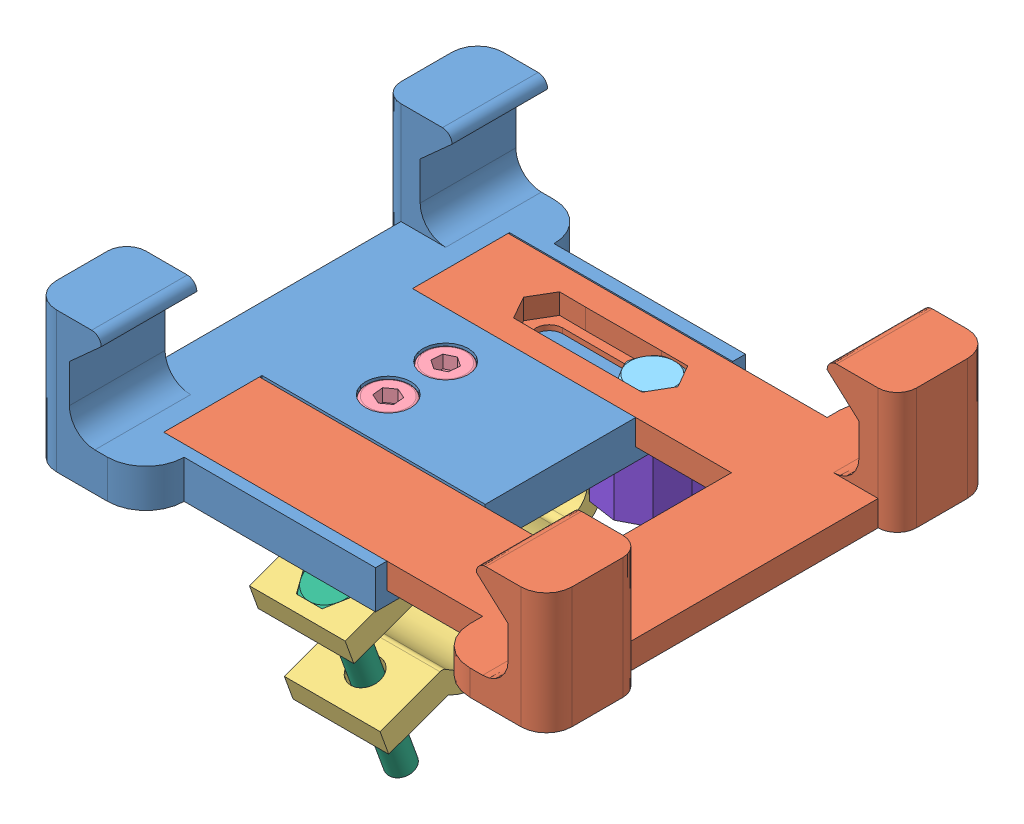
SolidWorks assembly Assemblagefinal, configuration Défaut. Lengths in mm.
Overall size (81 69.3 70.2).
12 component instances, 8 part files, 29 mates.
Components (placement in the parent):
- Support_droitV3_Upg-1: Support_droitV3_Upg [Défaut] at (-15.4658 -25.111 70) size (48 22 70)
- Support_gaucheV3_Upg-1: Support_gaucheV3_Upg [Défaut] at (10.8823 -7.9295 140.2) x (-1 0 0) z (0 0 -1) size (68 19 70)
- charnière_bisbis-1: charnière_bisbis [Défaut] at (-2.1366 -28.9295 101.2148) x (0.000205 -0.34202 0.939693) z (-1 0 0.000218) size (39.54 36.9 15)
- Vis à tête cylindrique à six pans creux Chc M4 - 10-1: Vis à tête cylindrique à six pans creux Chc M4 - 10 [Défaut] at (-9.6348 -8.1295 109.5) x (0.409825 0 -0.912164) z (0 -1 0) size (7 7 14)
- Vis à tête cylindrique à six pans creux Chc M4 - 10-2: Vis à tête cylindrique à six pans creux Chc M4 - 10 [Défaut] at (-9.6348 -8.1295 100.5) x (0.996961 0 0.077905) z (0 -1 0) size (7 7 14)
- Vis à tête hexagonale H M4 - 10-1: Vis à tête hexagonale H M4 - 10 [Défaut] at (7.8652 -7.1295 85.6045) x (0 0 -1) z (0 -1 0) size (7 8.08 12.8)
- Vis à tête hexagonale H M4 - 30-1: Vis à tête hexagonale H M4 - 30 [Défaut] at (-9.633 -27.2448 117.6392) x (-0.865923 -0.17101 0.470035) z (-0.000075 -0.939693 -0.34202) size (7 8.08 32.8)
- Ecrou M4-1: Ecrou M4 [Défaut] at (-9.6343 -43.4075 111.7564) x (0.866128 -0.17101 0.469658) z (0.000075 0.939693 0.34202) size (7 8.08 3.2)
- Ecrou M4-2: Ecrou M4 [Défaut] at (-9.6348 -16.1295 100.5) x (0.865916 0 -0.500189) z (0 -1 0) size (7 8.08 3.2)
- Ecrou M4-3: Ecrou M4 [Défaut] at (-9.6348 -16.1295 109.5) x (0.854192 0 -0.519958) z (0 -1 0) size (7 8.08 3.2)
- vissage-1: vissage [Défaut] at (7.8652 -19.9295 85.6045) x (1 0 0) z (0 1 0) size (14.56 14.51 10)
- Ecrou M4-4: Ecrou M4 [Défaut] at (7.8652 -17.1295 85.6045) x (0.929743 0 -0.368209) z (0 -1 0) size (7 8.08 3.2)
Mates (geometry in assembly coordinates):
- Coïncidente4: coincident anti-aligned: plane of Support_droitV3_Upg-1 through (-22.1348 -3.9295 93.2) normal (0 0 -1); plane of Support_gaucheV3_Upg-1 through (-22.1348 -3.9295 93.2) normal (0 0 1)
- Coïncidente5: coincident anti-aligned: plane of Support_droitV3_Upg-1 through (-22.1348 -7.9295 78) normal (0 1 0); plane of Support_gaucheV3_Upg-1 through (42.8652 -7.9295 70.2) normal (0 -1 0)
- DistanceLimite2: limit distance = 0 mm anti-aligned: plane of Support_droitV3_Upg-1 through (-22.1348 -25.111 70) normal (1 0 0); plane of Support_gaucheV3_Upg-1 through (-22.1348 -7.9295 140.2) normal (-1 0 0)
- Coaxiale1: concentric anti-aligned: cylinder of Support_droitV3_Upg-1 through (-9.6348 12.0715 109.5) axis (0 -1 0) radius 2.1; cylinder of charnière_bisbis-1 through (-9.6348 -12.9295 109.5) axis (0 1 0) radius 2.1
- Coïncidente7: coincident anti-aligned: plane of Support_droitV3_Upg-1 through (-32.1348 -9.9295 140) normal (0 -1 0); plane of charnière_bisbis-1 through (-17.1366 -9.9295 101.2181) normal (0 1 0)
- Coaxiale2: concentric aligned: cylinder of Support_droitV3_Upg-1 through (-9.6348 12.0715 109.5) axis (0 -1 0) radius 2.1; cylinder of Vis à tête cylindrique à six pans creux Chc M4 - 10-1 through (-9.6348 -8.1295 109.5) axis (0 -1 0) radius 2
- Coïncidente8: coincident anti-aligned: plane of Support_droitV3_Upg-1 through (-9.6348 -8.1295 109.5) normal (0 1 0); plane of Vis à tête cylindrique à six pans creux Chc M4 - 10-1 through (-9.6348 -8.1295 109.5) normal (0 -1 0)
- Coaxiale3: concentric aligned: cylinder of Support_droitV3_Upg-1 through (-9.6348 12.0715 100.5) axis (0 -1 0) radius 2.1; cylinder of Vis à tête cylindrique à six pans creux Chc M4 - 10-2 through (-9.6348 -8.1295 100.5) axis (0 -1 0) radius 2
- Coïncidente9: coincident anti-aligned: plane of Support_droitV3_Upg-1 through (-9.6348 -8.1295 100.5) normal (0 1 0); plane of Vis à tête cylindrique à six pans creux Chc M4 - 10-2 through (-9.6348 -8.1295 100.5) normal (0 -1 0)
- Coaxiale4: concentric anti-aligned: cylinder of Support_droitV3_Upg-1 through (7.8652 -9.9305 85.6045) axis (0 1 0) radius 2.1; cylinder of Vis à tête hexagonale H M4 - 10-1 through (7.8652 -7.1295 85.6045) axis (0 -1 0) radius 2
- Parallèle1: parallel anti-aligned: plane of Support_gaucheV3_Upg-1 through (10.8823 -7.1295 82.125) normal (0 0 1); plane of Vis à tête hexagonale H M4 - 10-1 through (5.8445 -4.3295 82.1045) normal (0 0 -1)
- Coïncidente11: coincident anti-aligned: plane of Support_gaucheV3_Upg-1 through (10.8823 -7.1295 140.2) normal (0 1 0); plane of Vis à tête hexagonale H M4 - 10-1 through (9.886 -7.1295 82.1045) normal (0 -1 0)
- Coaxiale5: concentric anti-aligned: cylinder of charnière_bisbis-1 through (-9.6328 -24.6136 118.5968) axis (0.000075 0.939693 0.34202) radius 2.4; cylinder of Vis à tête hexagonale H M4 - 30-1 through (-9.633 -27.2448 117.6392) axis (-0.000075 -0.939693 -0.34202) radius 2
- Coïncidente12: coincident anti-aligned: plane of charnière_bisbis-1 through (-2.136 -22.1637 103.6773) normal (0.000075 0.939693 0.34202); plane of Vis à tête hexagonale H M4 - 30-1 through (-13.6744 -27.2448 117.6401) normal (-0.000075 -0.939693 -0.34202)
- Coïncidente13: coincident anti-aligned: plane of charnière_bisbis-1 through (-11.6526 -22.9916 122.9123) normal (-0.000205 0.34202 -0.939693); plane of Vis à tête hexagonale H M4 - 30-1 through (-7.6113 -25.8107 121.8853) normal (0.000205 -0.34202 0.939693)
- Coaxiale6: concentric aligned: cylinder of Vis à tête hexagonale H M4 - 30-1 through (-9.633 -27.2448 117.6392) axis (-0.000075 -0.939693 -0.34202) radius 2; cylinder of Ecrou M4-1 through (-9.6345 -46.4145 110.662) axis (-0.000075 -0.939693 -0.34202) radius 1.65
- Coïncidente14: coincident anti-aligned: plane of charnière_bisbis-1 through (-17.1373 -38.3264 97.7979) normal (-0.000075 -0.939693 -0.34202); plane of Ecrou M4-1 through (-9.6357 -41.0134 105.1786) normal (0.000075 0.939693 0.34202)
- Parallèle2: parallel aligned: plane of charnière_bisbis-1 through (-17.1324 -35.8917 120.3466) normal (0.000205 -0.34202 0.939693); plane of Ecrou M4-1 through (-7.6131 -47.6116 113.9505) normal (0.000205 -0.34202 0.939693)
- Coaxiale8: concentric anti-aligned: cylinder of Vis à tête cylindrique à six pans creux Chc M4 - 10-2 through (-9.6348 -8.1295 100.5) axis (0 -1 0) radius 2; cylinder of Ecrou M4-2 through (-9.6348 -12.9295 100.5) axis (0 1 0) radius 1.65
- Coïncidente16: coincident anti-aligned: plane of charnière_bisbis-1 through (-2.1366 -12.9295 101.2148) normal (0 -1 0); plane of Ecrou M4-2 through (-9.6332 -12.9295 107.5) normal (0 1 0)
- Coïncidente17: coincident anti-aligned: plane of charnière_bisbis-1 through (-11.6582 -49.5185 97.0038) normal (0.866134 0 0.499811); plane of Ecrou M4-2 through (-13.6762 -12.9295 100.5009) normal (-0.866134 0 -0.499811)
- Coaxiale9: concentric anti-aligned: cylinder of Vis à tête cylindrique à six pans creux Chc M4 - 10-1 through (-9.6348 -8.1295 109.5) axis (0 -1 0) radius 2; cylinder of Ecrou M4-3 through (-9.6348 -12.9295 109.5) axis (0 1 0) radius 1.65
- Coïncidente18: coincident anti-aligned: plane of charnière_bisbis-1 through (-2.1366 -12.9295 101.2148) normal (0 -1 0); plane of Ecrou M4-3 through (-9.4724 -12.9295 116.4981) normal (0 1 0)
- Parallèle3: parallel anti-aligned: plane of charnière_bisbis-1 through (-5.5944 -49.5185 109.4096) normal (-0.854192 0 0.519958); plane of Ecrou M4-3 through (-7.6958 -12.9295 105.9541) normal (0.854192 0 -0.519958)
- Coaxiale10: concentric anti-aligned: cylinder of Vis à tête hexagonale H M4 - 10-1 through (7.8652 -7.1295 85.6045) axis (0 -1 0) radius 2; cylinder of vissage-1 through (7.8652 -13.9295 85.6045) axis (0 1 0) radius 2.1
- Coïncidente19: coincident anti-aligned: plane of Support_droitV3_Upg-1 through (-32.1348 -9.9295 140) normal (0 -1 0); plane of vissage-1 through (7.8652 -9.9295 85.6045) normal (0 1 0)
- Coaxiale11: concentric anti-aligned: cylinder of Vis à tête hexagonale H M4 - 10-1 through (7.8652 -7.1295 85.6045) axis (0 -1 0) radius 2; cylinder of Ecrou M4-4 through (7.8652 -13.9295 85.6045) axis (0 1 0) radius 1.65
- Coïncidente20: coincident anti-aligned: plane of vissage-1 through (7.8652 -13.9295 85.6045) normal (0 -1 0); plane of Ecrou M4-4 through (6.8433 -13.9295 92.5295) normal (0 1 0)
- Parallèle4: parallel anti-aligned: plane of vissage-1 through (9.3746 -9.9295 89.4157) normal (-0.78375 0 -0.621077); plane of Ecrou M4-4 through (11.8634 -13.9295 86.1946) normal (0.78375 0 0.621077)
